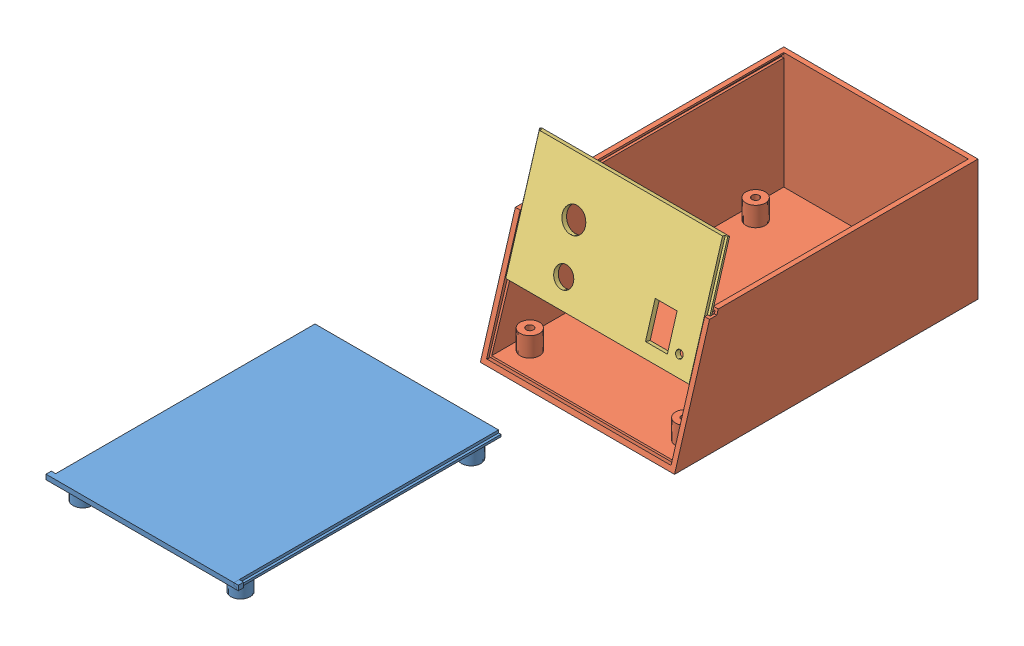
SolidWorks assembly Assembly ECG, configuration Default. Lengths in mm.
Overall size (80 73.02 304.36).
3 component instances, 3 part files, 5 mates.
Components (placement in the parent):
- Design 2 cover 2-1: Design 2 cover 2 [Default] at (-15.354 47.0384 119.9265) size (79.2 10 109)
- Design 2-1: Design 2 [Default] at (63.373 35.873 -75.7896) x (0 0 1) z (0 -1 0) size (125 80 50)
- Design 2 cover 1-2: Design 2 cover 1 [Default] at (-15.254 25.51 -69.4648) x (1 0 0) z (0 -0.957826 0.287348) size (77.5 2 48)
Mates (geometry in assembly coordinates):
- Coincident3: coincident aligned: plane of Design 2 cover 2-1 through (-15.354 49.0384 119.9265) normal (0 1 0); plane of Design 2-1 through (-16.627 49.0384 -184.4352) normal (0 1 0)
- Distance2: distance = 0.127 mm: line of Design 2 cover 2-1 through (61.246 49.0384 10.9265) axis (0 0 1); line of Design 2-1 through (61.373 49.0384 -77.4352) axis (0 0 -1)
- Parallel4: parallel aligned: line of Design 2-1 through (-14.627 0.954 -60.0099) axis (1 0 0); line of Design 2 cover 1-2 through (-14.254 26.0847 -67.5491) axis (1 0 0)
- Coincident7: coincident aligned: plane of Design 2-1 through (-16.627 49.0384 -74.4352) normal (0 0.287348 0.957826); plane of Design 2 cover 1-2 through (-15.254 26.0847 -67.5491) normal (0 0.287348 0.957826)
- Distance1: distance = 0.127 mm: line of Design 2 cover 1-2 through (61.246 72.0604 -81.3418) axis (0 -0.957826 0.287348); line of Design 2-1 through (61.373 0.954 -60.0099) axis (0 0.957826 -0.287348)
